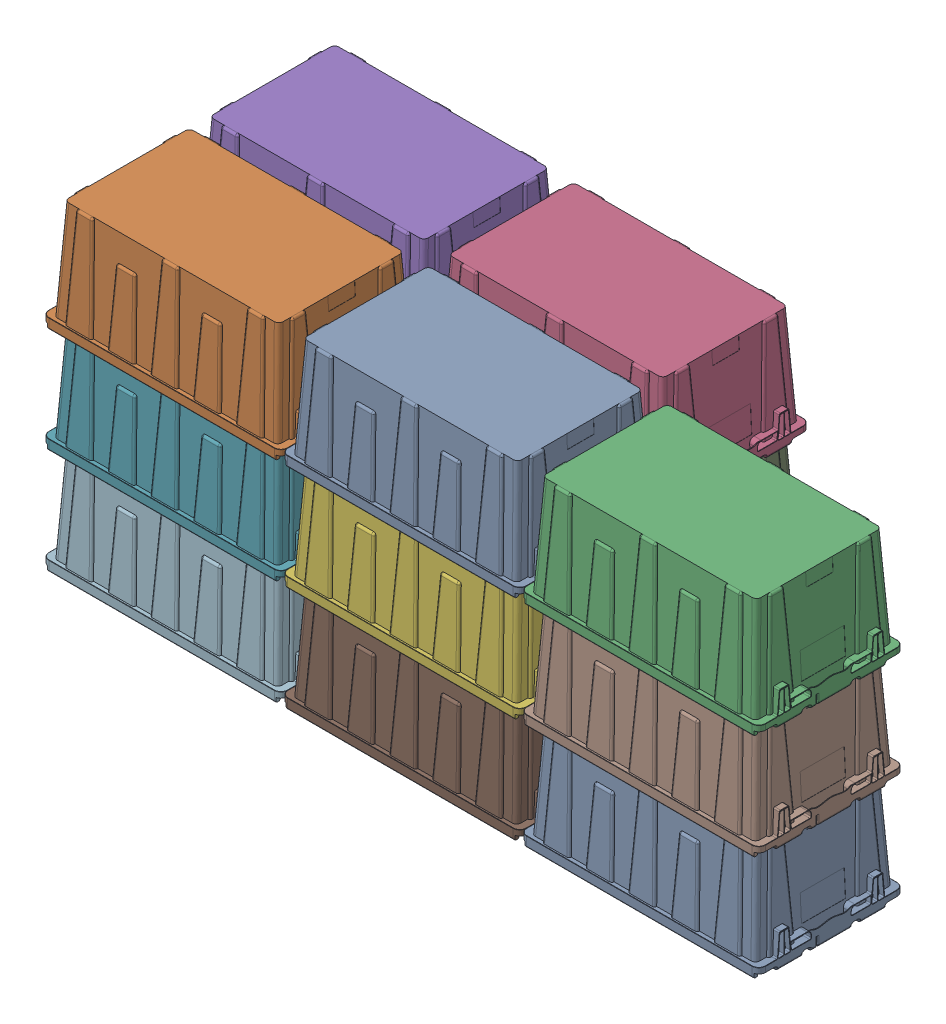
SolidWorks assembly ALLIANCE_STATION_GP2_ASM, configuration Default. Lengths in mm.
Overall size (2051.05 910.73 825.5).
15 component instances, 1 part files, 0 mates.
Components (placement in the parent):
- GRAY_TOTE-1: GRAY_TOTE [Default] at (339.725 0 0) x (0 -1 0) z (-1 0 0) size (313.83 412.75 692.15)
- GRAY_TOTE-2: GRAY_TOTE [Default] at (-339.725 0 0) x (0 -1 0) z (-1 0 0) size (313.83 412.75 692.15)
- GRAY_TOTE-3: GRAY_TOTE [Default] at (1019.175 0 0) x (0 -1 0) z (-1 0 0) size (313.83 412.75 692.15)
- GRAY_TOTE-4: GRAY_TOTE [Default] at (339.725 0 -412.75) x (0 -1 0) z (-1 0 0) size (313.83 412.75 692.15)
- GRAY_TOTE-5: GRAY_TOTE [Default] at (-339.725 0 -412.75) x (0 -1 0) z (-1 0 0) size (313.83 412.75 692.15)
- GRAY_TOTE-6: GRAY_TOTE [Default] at (339.725 -298.45 0) x (0 -1 0) z (-1 0 0) size (313.83 412.75 692.15)
- GRAY_TOTE-7: GRAY_TOTE [Default] at (-339.725 -298.45 0) x (0 -1 0) z (-1 0 0) size (313.83 412.75 692.15)
- GRAY_TOTE-8: GRAY_TOTE [Default] at (1019.175 -298.45 0) x (0 -1 0) z (-1 0 0) size (313.83 412.75 692.15)
- GRAY_TOTE-9: GRAY_TOTE [Default] at (339.725 -298.45 -412.75) x (0 -1 0) z (-1 0 0) size (313.83 412.75 692.15)
- GRAY_TOTE-10: GRAY_TOTE [Default] at (-339.725 -298.45 -412.75) x (0 -1 0) z (-1 0 0) size (313.83 412.75 692.15)
- GRAY_TOTE-11: GRAY_TOTE [Default] at (339.725 -596.9 0) x (0 -1 0) z (-1 0 0) size (313.83 412.75 692.15)
- GRAY_TOTE-12: GRAY_TOTE [Default] at (-339.725 -596.9 0) x (0 -1 0) z (-1 0 0) size (313.83 412.75 692.15)
- GRAY_TOTE-13: GRAY_TOTE [Default] at (1019.175 -596.9 0) x (0 -1 0) z (-1 0 0) size (313.83 412.75 692.15)
- GRAY_TOTE-14: GRAY_TOTE [Default] at (339.725 -596.9 -412.75) x (0 -1 0) z (-1 0 0) size (313.83 412.75 692.15)
- GRAY_TOTE-15: GRAY_TOTE [Default] at (-339.725 -596.9 -412.75) x (0 -1 0) z (-1 0 0) size (313.83 412.75 692.15)
